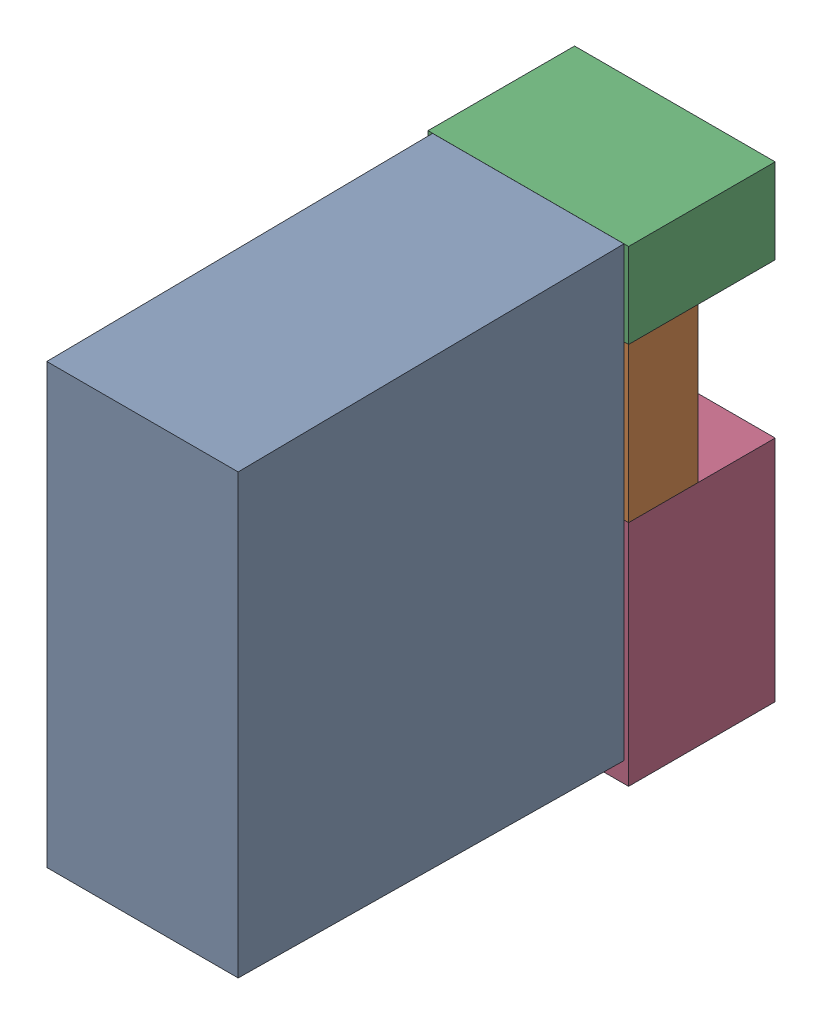
SolidWorks assembly K7, configuration Default. Lengths in mm.
Overall size (13 30.3 34.5).
7 component instances, 4 part files, 0 mates.
Components (placement in the parent):
- relais_40_61_8_006_0000-1: relais_40_61_8_006_0000 [Default] at (98.425 15.7216 9.5) x (0 1 0) z (1 0 0) size (29 30 12.4)
- 1151725064-1: 1151725064 [Default] at (98.425 34.225 5) size (13 10 4.5)
  - Extruded_3-1: Extruded_3 [Default] at origin size (13 10 4.5)
- 1151724928-1: 1151724928 [Default] at (98.425 41.975 0) size (13 5.5 9.5)
  - Extruded_2-1: Extruded_2 [Default] at origin size (13 5.5 9.5)
- 1151724792-1: 1151724792 [Default] at (98.425 21.825 0) size (13 14.8 9.5)
  - Extruded_4-1: Extruded_4 [Default] at origin size (13 14.8 9.5)
